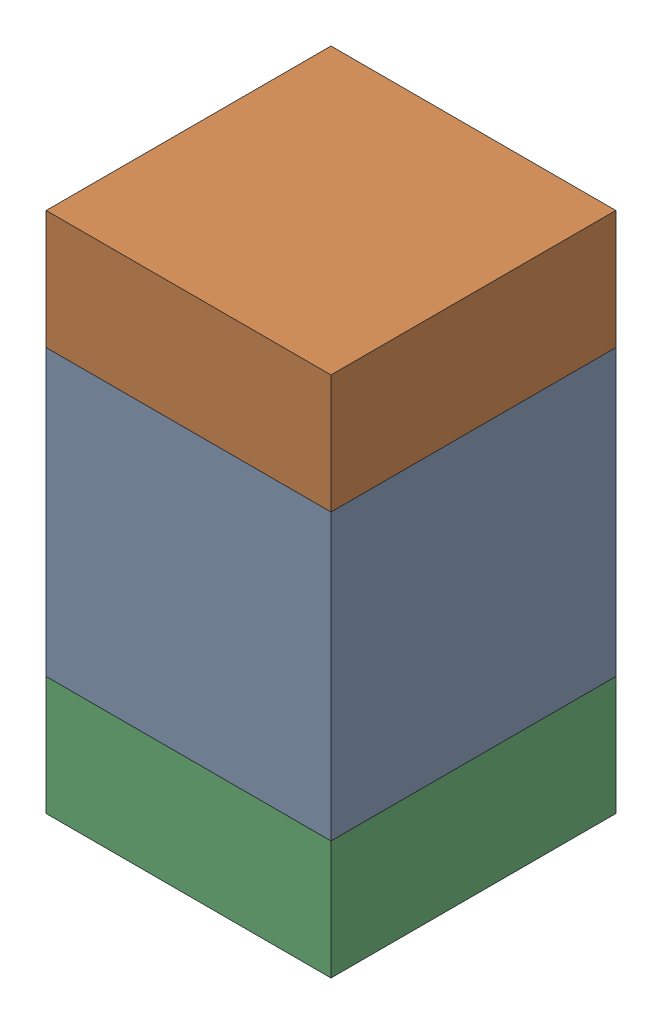
SolidWorks assembly C127_1PCB, configuration Default. Lengths in mm.
Overall size (0.6 1.1 0.6).
6 component instances, 2 part files, 0 mates.
Components (placement in the parent):
- 761606048-1: 761606048 [Default] at (102.9 121.3 0) size (0.6 0.6 0.6)
  - Extruded_9-1: Extruded_9 [Default] at origin size (0.6 0.6 0.6)
- 854785296-1: 854785296 [Default] at (102.9 121.725 0) size (0.6 0.25 0.6)
  - Extruded_10-1: Extruded_10 [Default] at origin size (0.6 0.25 0.6)
- 854785296-2: 854785296 [Default] at (102.9 120.875 0) size (0.6 0.25 0.6)
  - Extruded_10-1: Extruded_10 [Default] at origin size (0.6 0.25 0.6)
